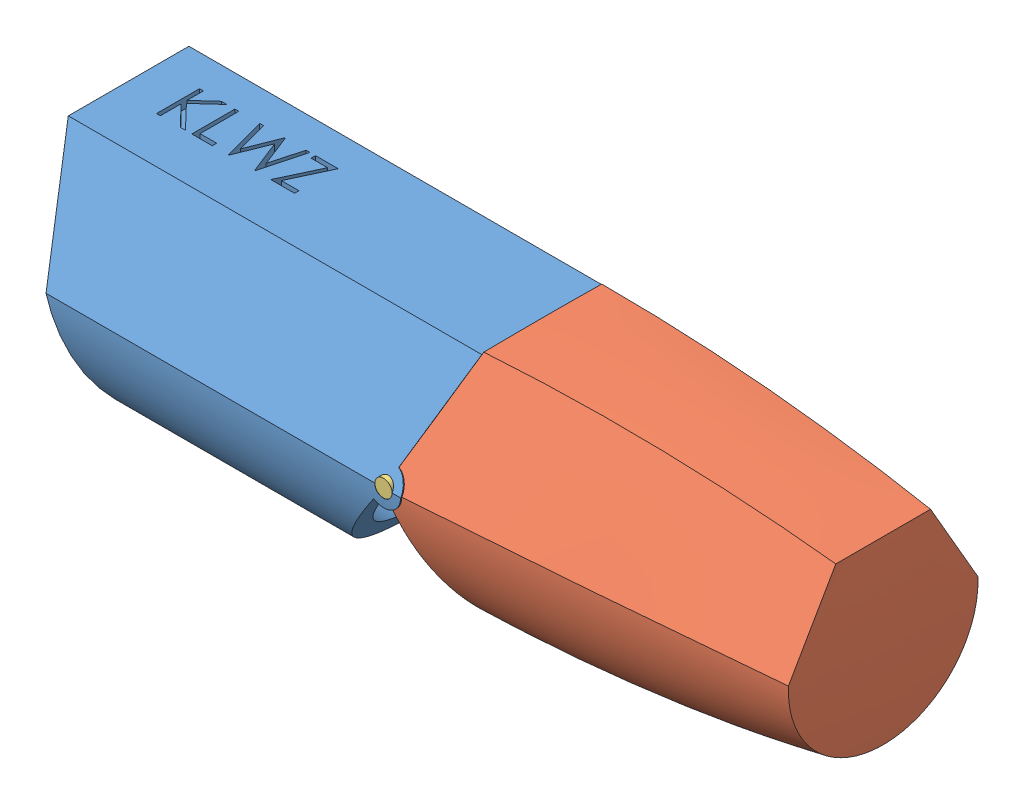
SolidWorks assembly Thumb Finger-KLWZ, configuration Default. Lengths in mm.
Overall size (55.96 18.36 17.96).
8 component instances, 5 part files, 9 mates.
Components (placement in the parent):
- Thumb Bottom-KLWZ-1: Thumb Bottom-KLWZ [Default] at (-12.3688 24.9437 27.5572) size (30.48 17.11 17.82)
- Thumb Tip-KLWZ-1: Thumb Tip-KLWZ [Default] at (15.309 24.9437 27.5572) size (29.55 18.36 17.96)
- Hinge Pin-KLWZ-1: Hinge Pin-KLWZ [Default] at (15.309 17.2447 18.6672) x (1 0 0) z (0 -1 0) size (1.27 1.52 1.27)
- Hinge Pin-KLWZ-2: Hinge Pin-KLWZ [Default] at (15.309 17.2447 34.9232) x (1 0 0) z (0 -1 0) size (1.27 1.52 1.27)
- Hinge 3-KLWZ-1: Hinge 3-KLWZ [Default] at (-8.2616 6.2764 25.0218) x (0.998734 -0.050311 0) z (0 0 1) size (2.55 0.58 2.54) (flexible)
  - Hinge 3-KLWZ-1: Hinge 3-KLWZ [Default] at (1.5197 1.8887 1.2654) size (1.52 0.51 2.54)
  - Hinge 3-KLWZ-2: Hinge 3-KLWZ [Default] at (1.5197 1.8887 3.8054) x (-0.998734 -0.050311 0) z (0 0 -1) size (1.52 0.51 2.54)
  - Hinge 3 Pin-KLWZ-1: Hinge 3 Pin-KLWZ [Default] at (1.5197 1.8887 3.8054) x (1 0 0) z (0 1 0) size (0.25 2.54 0.25)
Mates (geometry in assembly coordinates):
- Coincident1: coincident aligned: circle of Thumb Bottom-KLWZ-1; circle of Thumb Tip-KLWZ-1
- Coincident2: coincident anti-aligned: circle of Thumb Bottom-KLWZ-1; circle of Thumb Tip-KLWZ-1
- LimitAngle1: limit planar angle = 0 rad anti-aligned: plane of Thumb Tip-KLWZ-1 through (19.2518 28.0774 18.5972) normal (-0.939693 0.34202 0); plane of Thumb Bottom-KLWZ-1 through (18.1112 24.9437 18.6527) normal (0.939693 -0.34202 0)
- Concentric1: concentric anti-aligned: cylinder of Thumb Bottom-KLWZ-1 through (15.309 17.2447 18.6527) axis (0 0 1) radius 0.635; cylinder of Hinge Pin-KLWZ-1 through (15.309 17.2447 20.1912) axis (0 0 -1) radius 0.635
- Coincident4: coincident: point of Thumb Bottom-KLWZ-1; circle of Hinge Pin-KLWZ-1
- Concentric2: concentric anti-aligned: cylinder of Thumb Bottom-KLWZ-1 through (15.309 17.2447 18.6527) axis (0 0 1) radius 0.635; cylinder of Hinge Pin-KLWZ-2 through (15.309 17.2447 36.4472) axis (0 0 -1) radius 0.635
- Coincident5: coincident: point of Thumb Bottom-KLWZ-1; circle of Hinge Pin-KLWZ-2
- Coincident6: coincident anti-aligned: line of Thumb Bottom-KLWZ-1 through (-5.3787 8.3402 28.8272) axis (0 0 -1); line of Hinge 3-KLWZ-1/Hinge 3-KLWZ-2 through (-5.3787 8.3402 26.2872) axis (0 0 1)
- Coincident7: coincident aligned: line of Thumb Bottom-KLWZ-1 through (-6.3256 8.3402 28.8272) axis (1 0 0); line of Hinge 3-KLWZ-1/Hinge 3-KLWZ-2 through (-6.3947 8.3402 28.8272) axis (1 0 0)
